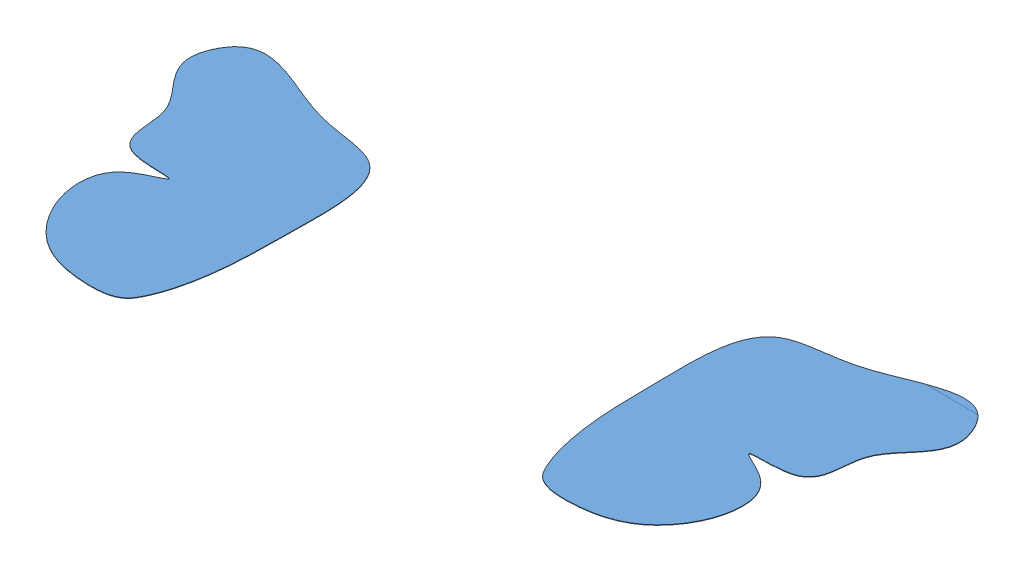
SolidWorks assembly visual_test_1, configuration Default. Lengths in mm.
Overall size (6935.96 24.56 3312.84).
2 component instances, 1 part files, 0 mates.
Components (placement in the parent):
- wing_photo-1: wing_photo [Default] at (-483.351 2235.6484 2400.3702) size (1971.42 4.13 2800.64)
- wing_photo-2: wing_photo [Default] at (7207.207 2216.0518 1888.1707) x (-0.999962 0.008727 0) z (0 0 1) size (1971.42 4.13 2800.64)
